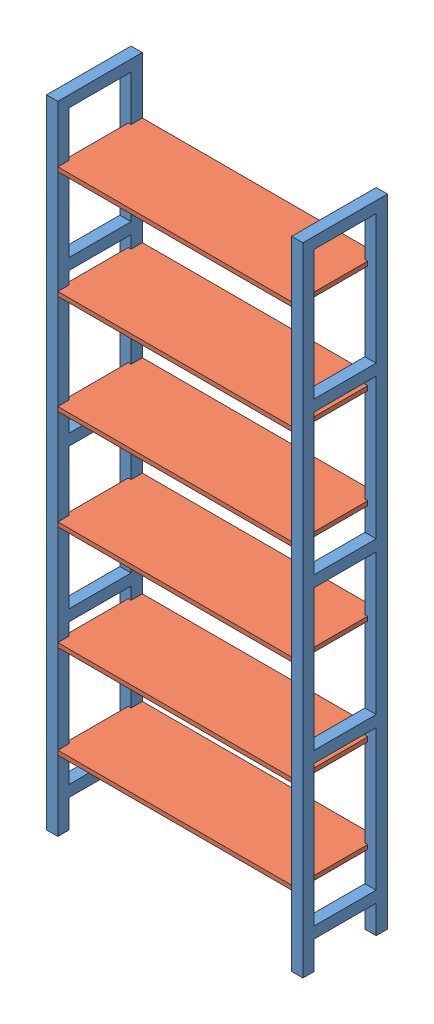
SolidWorks assembly Baugruppe1, configuration Standard. Lengths in mm.
Overall size (910 2260 300).
8 component instances, 2 part files, 15 mates.
Components (placement in the parent):
- Seite-30-226-1: Seite-30-226 [Standard] at (-238.8637 -1.8239 2260) size (40 2260 300)
- Seite-30-226-2: Seite-30-226 [Standard] at (631.1363 -1.8239 2260) size (40 2260 300)
- Boden-30-83-1: Boden-30-83 [Standard] at (216.1363 911.7275 2260) size (850 15 300)
- Boden-30-83-2: Boden-30-83 [Standard] at (216.1363 528.716 2260) size (850 15 300)
- Boden-30-83-3: Boden-30-83 [Standard] at (216.1363 174.8864 2260) size (850 15 300)
- Boden-30-83-4: Boden-30-83 [Standard] at (216.1363 -179.7181 2260) size (850 15 300)
- Boden-30-83-5: Boden-30-83 [Standard] at (216.1363 -550.7434 2260) size (850 15 300)
- Boden-30-83-6: Boden-30-83 [Standard] at (216.1363 -881.6449 2260) size (850 15 300)
Mates (geometry in assembly coordinates):
- Deckungsgleich1: coincident anti-aligned: plane of Seite-30-226-1 through (-198.8637 -1.8239 2260) normal (1 0 0); plane of Boden-30-83-1 through (-198.8637 926.7275 2370) normal (-1 0 0)
- Deckungsgleich2: coincident: plane of Seite-30-226-1 through (-198.8637 -1.8239 2260) normal (1 0 0); plane of Boden-30-83-2 through (-198.8637 543.716 2370) normal (-1 0 0)
- Deckungsgleich3: coincident: plane of Seite-30-226-1 through (-198.8637 -1.8239 2260) normal (1 0 0); plane of Boden-30-83-3 through (-198.8637 189.8864 2370) normal (-1 0 0)
- Deckungsgleich4: coincident: plane of Seite-30-226-1 through (-198.8637 -1.8239 2260) normal (1 0 0); plane of Boden-30-83-4 through (-198.8637 -164.7181 2370) normal (-1 0 0)
- Deckungsgleich5: coincident: plane of Seite-30-226-1 through (-198.8637 -1.8239 2260) normal (1 0 0); plane of Boden-30-83-6 through (-198.8637 -866.6449 2370) normal (-1 0 0)
- Deckungsgleich6: coincident aligned: plane of Seite-30-226-1 through (-198.8637 1128.1761 2410) normal (0 0 1); plane of Boden-30-83-6 through (-198.8637 -866.6449 2410) normal (0 0 1)
- Deckungsgleich7: coincident: plane of Seite-30-226-1 through (-198.8637 1128.1761 2410) normal (0 0 1); plane of Boden-30-83-5 through (-198.8637 -535.7434 2410) normal (0 0 1)
- Deckungsgleich8: coincident anti-aligned: plane of Seite-30-226-1 through (-198.8637 -1.8239 2260) normal (1 0 0); plane of Boden-30-83-5 through (-198.8637 -535.7434 2370) normal (-1 0 0)
- Deckungsgleich9: coincident aligned: plane of Seite-30-226-1 through (-198.8637 1128.1761 2410) normal (0 0 1); plane of Boden-30-83-4 through (-198.8637 -164.7181 2410) normal (0 0 1)
- Deckungsgleich10: coincident aligned: plane of Seite-30-226-1 through (-198.8637 1128.1761 2410) normal (0 0 1); plane of Boden-30-83-3 through (-198.8637 189.8864 2410) normal (0 0 1)
- Deckungsgleich11: coincident aligned: plane of Seite-30-226-1 through (-198.8637 1128.1761 2410) normal (0 0 1); plane of Boden-30-83-2 through (-198.8637 543.716 2410) normal (0 0 1)
- Deckungsgleich12: coincident aligned: plane of Seite-30-226-1 through (-198.8637 1128.1761 2410) normal (0 0 1); plane of Boden-30-83-1 through (-198.8637 926.7275 2410) normal (0 0 1)
- Deckungsgleich13: coincident aligned: plane of Seite-30-226-2 through (671.1363 1128.1761 2410) normal (0 0 1); plane of Boden-30-83-1 through (-198.8637 926.7275 2410) normal (0 0 1)
- Deckungsgleich14: coincident anti-aligned: plane of Seite-30-226-2 through (631.1363 -1.8239 2260) normal (-1 0 0); plane of Boden-30-83-1 through (631.1363 926.7275 2410) normal (1 0 0)
- Deckungsgleich15: coincident aligned: plane of Seite-30-226-1 through (-198.8637 1128.1761 2410) normal (0 1 0); plane of Seite-30-226-2 through (671.1363 1128.1761 2410) normal (0 1 0)
